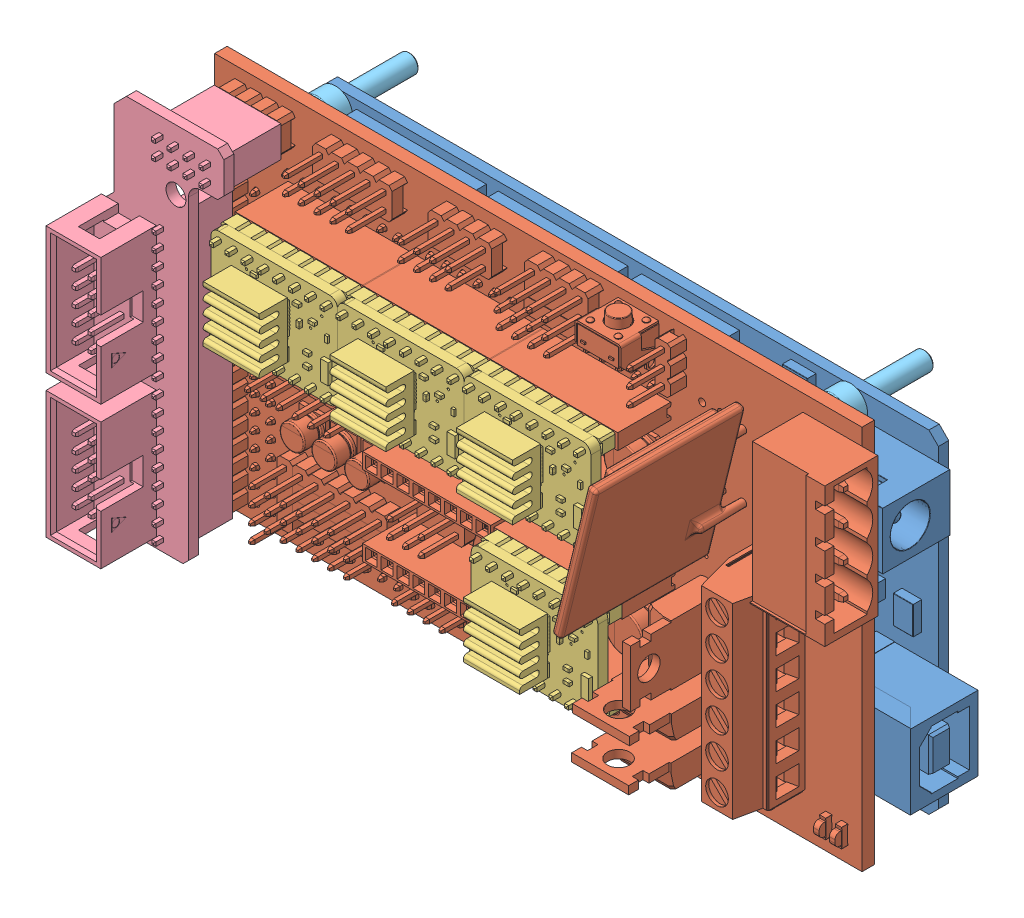
SolidWorks assembly Assembly ramps, configuration Valor predeterminado. Lengths in mm.
Overall size (115.32 62.9 52.19).
11 component instances, 5 part files, 27 mates.
Components (placement in the parent):
- Arduino Mega 2560-1: Arduino Mega 2560 [Valor predeterminado] at (56.9957 20.5833 22.5398) x (1 0 0) z (0 0 -1) size (107.95 53.42 12.95)
- Shield Ramps 1.4-2: Shield Ramps 1.4 [Valor predeterminado] at (108.6536 24.5502 33.656) x (0 1 0) z (1 0 0) size (61.76 37.63 106.38)
- Driver A4988-1: Driver A4988 [Valor predeterminado] at (87.719 94.2785 46.462) x (-1 0 0) z (0 0 1) size (20.32 15.24 16.04)
- Driver A4988-2: Driver A4988 [Valor predeterminado] at (108.039 94.2785 46.462) x (-1 0 0) z (0 0 1) size (20.32 15.24 16.04)
- Driver A4988-3: Driver A4988 [Valor predeterminado] at (128.359 94.2785 46.462) x (-1 0 0) z (0 0 1) size (20.32 15.24 16.04)
- Driver A4988-4: Driver A4988 [Valor predeterminado] at (129.4895 71.2863 46.462) x (-1 0 0) z (0 0 1) size (20.32 15.24 16.04)
- Smart adapter conector LCD Ramps 1.4-1: Smart adapter conector LCD Ramps 1.4 [Valor predeterminado] at (11.2712 45.3827 46.7332) x (-1 0 0) z (0 1 0) size (20.12 19 60.45)
- Screw DIN 912 - M3 x 12 --- 12N-1: Screw DIN 912 - M3 x 12 --- 12N [Valor predeterminado] at (18.5401 -3.5848 25.5398) x (0 0 1) z (-0.824414 0.565988 0) size (15 5.5 5.5)
- Screw DIN 912 - M3 x 12 --- 12N-2: Screw DIN 912 - M3 x 12 --- 12N [Valor predeterminado] at (93.6733 -3.5848 25.5398) x (0 0 1) z (-0.656552 0.754281 0) size (15 5.5 5.5)
- Screw DIN 912 - M3 x 12 --- 12N-3: Screw DIN 912 - M3 x 12 --- 12N [Valor predeterminado] at (11.0471 44.7514 25.5398) x (0 0 1) z (-0.824414 0.565988 0) size (15 5.5 5.5)
- Screw DIN 912 - M3 x 12 --- 12N-4: Screw DIN 912 - M3 x 12 --- 12N [Valor predeterminado] at (93.6733 44.7514 25.5398) x (0 0 1) z (-0.824414 0.565988 0) size (15 5.5 5.5)
Mates (geometry in assembly coordinates):
- Coincidente23: coincident: plane of assembly; plane of assembly; plane of Arduino Mega 2560-1 through (86.5359 -2.391 31.0996) normal (0 0 1); plane of Shield Ramps 1.4-2 through (12.7997 -6.3634 31.0996) normal (0 0 -1)
- Paralelo8: parallel: plane of assembly; plane of assembly; plane of Arduino Mega 2560-1 through (65.7841 -4.8548 31.0996) normal (0 -1 0); plane of Shield Ramps 1.4-2 through (108.6536 -6.3322 25.656) normal (0 -1 0)
- Coincidente25: coincident: plane of assembly; plane of assembly; plane of Arduino Mega 2560-1 through (43.0511 -4.8548 31.0996) normal (0 -1 0); plane of Shield Ramps 1.4-2 through (23.6897 -4.8548 31.116) normal (0 -1 0)
- Coincidente26: coincident: plane of assembly; plane of assembly; plane of Arduino Mega 2560-1 through (10.2597 -4.9056 31.0996) normal (-1 0 0); plane of Shield Ramps 1.4-2 through (10.2597 -1.8338 31.0996) normal (-1 0 0)
- Coincidente27: coincident: plane of assembly; plane of assembly; plane of Shield Ramps 1.4-2 through (16.599 28.2385 44.172) normal (0 -1 0); plane of Driver A4988-1 through (26.759 28.2385 46.462) normal (0 -1 0)
- Coincidente28: coincident: plane of assembly; plane of assembly; plane of Shield Ramps 1.4-2 through (16.599 30.7385 44.172) normal (0 0 1); plane of Driver A4988-1 through (33.109 29.4835 44.172) normal (0 0 -1)
- Coincidente29: coincident: plane of assembly; plane of assembly; plane of Shield Ramps 1.4-2 through (16.599 43.1135 35.822) normal (-1 0 0); plane of Driver A4988-1 through (16.599 28.2385 46.462) normal (-1 0 0)
- Coincidente30: coincident: plane of assembly; plane of assembly; plane of Shield Ramps 1.4-2 through (37.009 28.2385 44.172) normal (0 -1 0); plane of Driver A4988-2 through (44.539 28.2385 46.462) normal (0 -1 0)
- Coincidente31: coincident: plane of assembly; plane of assembly; plane of Shield Ramps 1.4-2 through (37.009 30.7385 44.172) normal (0 0 1); plane of Driver A4988-2 through (40.729 29.4835 44.172) normal (0 0 -1)
- Coincidente32: coincident: plane of assembly; plane of assembly; plane of Driver A4988-1 through (36.919 30.7285 46.462) normal (1 0 0); plane of Driver A4988-2 through (36.919 28.2385 46.462) normal (-1 0 0)
- Coincidente33: coincident: plane of assembly; plane of assembly; plane of Shield Ramps 1.4-2 through (57.419 28.2385 44.172) normal (0 -1 0); plane of Driver A4988-3 through (69.939 28.2385 46.462) normal (0 -1 0)
- Coincidente34: coincident: plane of assembly; plane of assembly; plane of Shield Ramps 1.4-2 through (57.419 30.7385 44.172) normal (0 0 1); plane of Driver A4988-3 through (61.049 29.4835 44.172) normal (0 0 -1)
- Coincidente35: coincident: plane of assembly; plane of assembly; plane of Driver A4988-2 through (57.239 30.7285 46.462) normal (1 0 0); plane of Driver A4988-3 through (57.239 28.2385 46.462) normal (-1 0 0)
- Coincidente36: coincident: plane of assembly; plane of assembly; plane of Shield Ramps 1.4-2 through (58.1195 7.7463 44.172) normal (0 0 1); plane of Driver A4988-4 through (72.3395 6.4913 44.172) normal (0 0 -1)
- Coincidente37: coincident: plane of assembly; plane of assembly; plane of Shield Ramps 1.4-2 through (58.1195 5.2463 44.172) normal (0 -1 0); plane of Driver A4988-4 through (73.6095 5.2463 46.462) normal (0 -1 0)
- Coincidente38: coincident: plane of assembly; plane of assembly; plane of Shield Ramps 1.4-2 through (78.6895 7.2713 35.822) normal (1 0 0); plane of Driver A4988-4 through (78.6895 7.7363 46.462) normal (1 0 0)
- Coincidente39: coincident: plane of assembly; plane of assembly; plane of Shield Ramps 1.4-2 through (10.2112 38.4311 38.2332) normal (0 0 1); plane of Smart adapter conector LCD Ramps 1.4-1 through (8.9412 18.0077 38.2332) normal (0 0 -1)
- Coincidente40: coincident: plane of assembly; plane of assembly; plane of Shield Ramps 1.4-2 through (10.2112 2.3011 38.2332) normal (1 0 0); plane of Smart adapter conector LCD Ramps 1.4-1 through (10.2112 41.2327 38.2332) normal (1 0 0)
- Coincidente41: coincident: plane of assembly; plane of assembly; plane of Shield Ramps 1.4-2 through (17.2487 53.5727 38.156) normal (0 1 0); plane of Smart adapter conector LCD Ramps 1.4-1 through (18.0112 53.5727 38.2332) normal (0 1 0)
- Concêntrico1: concentric: cylinder of assembly; cylinder of assembly; cylinder of Arduino Mega 2560-1 through (18.5401 -3.5848 20.8878) axis (0 0 1) radius 1.5621; cylinder of Screw DIN 912 - M3 x 12 --- 12N-1 through (18.5401 -3.5848 25.5398) axis (0 0 1) radius 1.5
- Coincidente42: coincident: plane of assembly; plane of assembly; plane of Arduino Mega 2560-1 through (107.7957 47.2914 22.5398) normal (0 0 1); plane of Screw DIN 912 - M3 x 12 --- 12N-1 through (20.0966 -1.3177 22.5398) normal (0 0 -1)
- Concêntrico2: concentric: cylinder of assembly; cylinder of assembly; cylinder of Arduino Mega 2560-1 through (93.6733 -3.5848 20.8878) axis (0 0 1) radius 1.5621; cylinder of Screw DIN 912 - M3 x 12 --- 12N-2 through (93.6733 -3.5848 25.5398) axis (0 0 1) radius 1.5
- Coincidente43: coincident: plane of assembly; plane of assembly; plane of Arduino Mega 2560-1 through (107.7957 47.2914 22.5398) normal (0 0 1); plane of Screw DIN 912 - M3 x 12 --- 12N-2 through (95.7476 -1.7793 22.5398) normal (0 0 -1)
- Concêntrico3: concentric: cylinder of assembly; cylinder of assembly; cylinder of Arduino Mega 2560-1 through (11.0471 44.7514 20.8878) axis (0 0 1) radius 1.5621; cylinder of Screw DIN 912 - M3 x 12 --- 12N-3 through (11.0471 44.7514 25.5398) axis (0 0 1) radius 1.5
- Coincidente44: coincident: plane of assembly; plane of assembly; plane of Arduino Mega 2560-1 through (107.7957 47.2914 22.5398) normal (0 0 1); plane of Screw DIN 912 - M3 x 12 --- 12N-3 through (12.6036 47.0185 22.5398) normal (0 0 -1)
- Concêntrico4: concentric: cylinder of assembly; cylinder of assembly; cylinder of Arduino Mega 2560-1 through (93.6733 44.7514 20.8878) axis (0 0 1) radius 1.5621; cylinder of Screw DIN 912 - M3 x 12 --- 12N-4 through (93.6733 44.7514 25.5398) axis (0 0 1) radius 1.5
- Coincidente45: coincident: plane of assembly; plane of assembly; plane of Arduino Mega 2560-1 through (107.7957 47.2914 22.5398) normal (0 0 1); plane of Screw DIN 912 - M3 x 12 --- 12N-4 through (95.2298 47.0185 22.5398) normal (0 0 -1)
